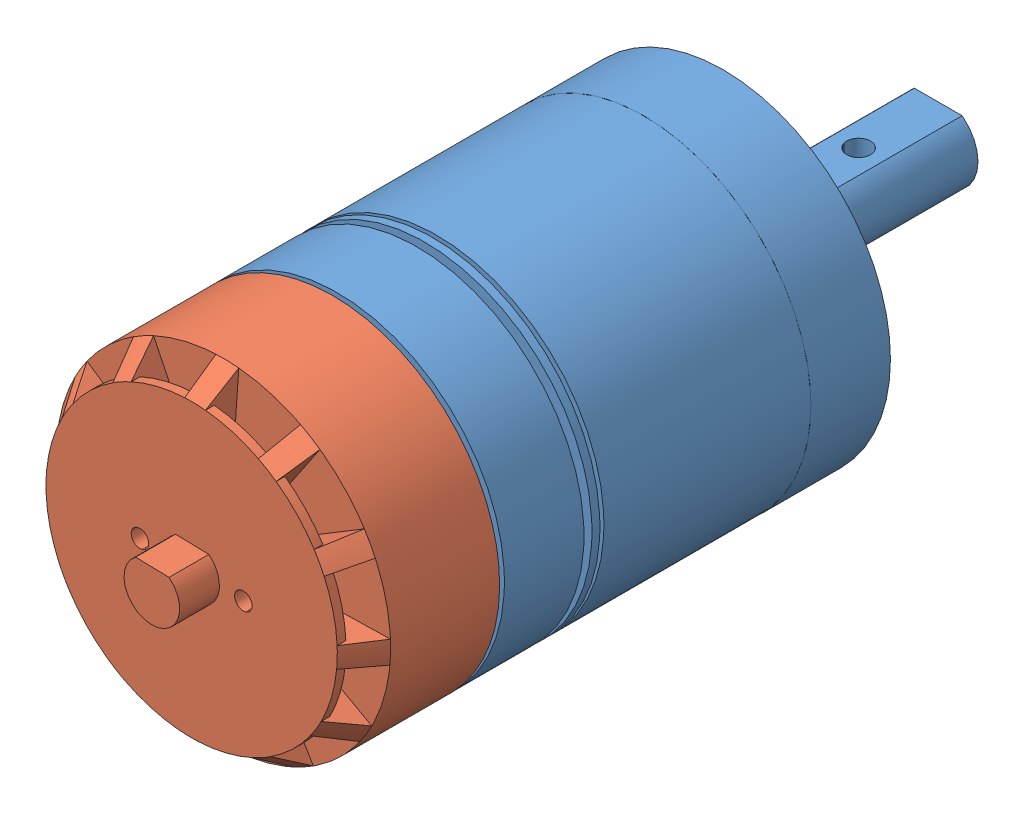
SolidWorks assembly 3508 电机, configuration 默认. Lengths in mm.
Overall size (52.13 52.13 98.8).
2 component instances, 2 part files, 2 mates.
Components (placement in the parent):
- 复件 3508减速^3508 电机-2: 复件 3508减速^3508 电机 [默认] at (-10.9051 0.765 71.75) size (42 42 75.5) (virtual)
- 复件 3508电机屁股^3508 电机-2: 复件 3508电机屁股^3508 电机 [默认] at (-10.9051 0.765 120.85) x (0.959543 -0.281562 0) z (0 0 1) size (42 42 22.7) (virtual)
Mates (geometry in assembly coordinates):
- 同心1: concentric aligned: cylinder of 复件 3508减速^3508 电机-2 through (-10.9051 0.765 81.75) axis (0 0 -1) radius 21; cylinder of 3508电机屁股-2 through (-10.9051 0.765 134.55) axis (0 0 -1) radius 21
- 距离1: distance = 66.8 mm anti-aligned: plane of 复件 3508减速^3508 电机-2 through (-10.9051 0.765 71.75) normal (0 0 -1); plane of 3508电机屁股-2 through (-10.9051 0.765 138.55) normal (0 0 1)
